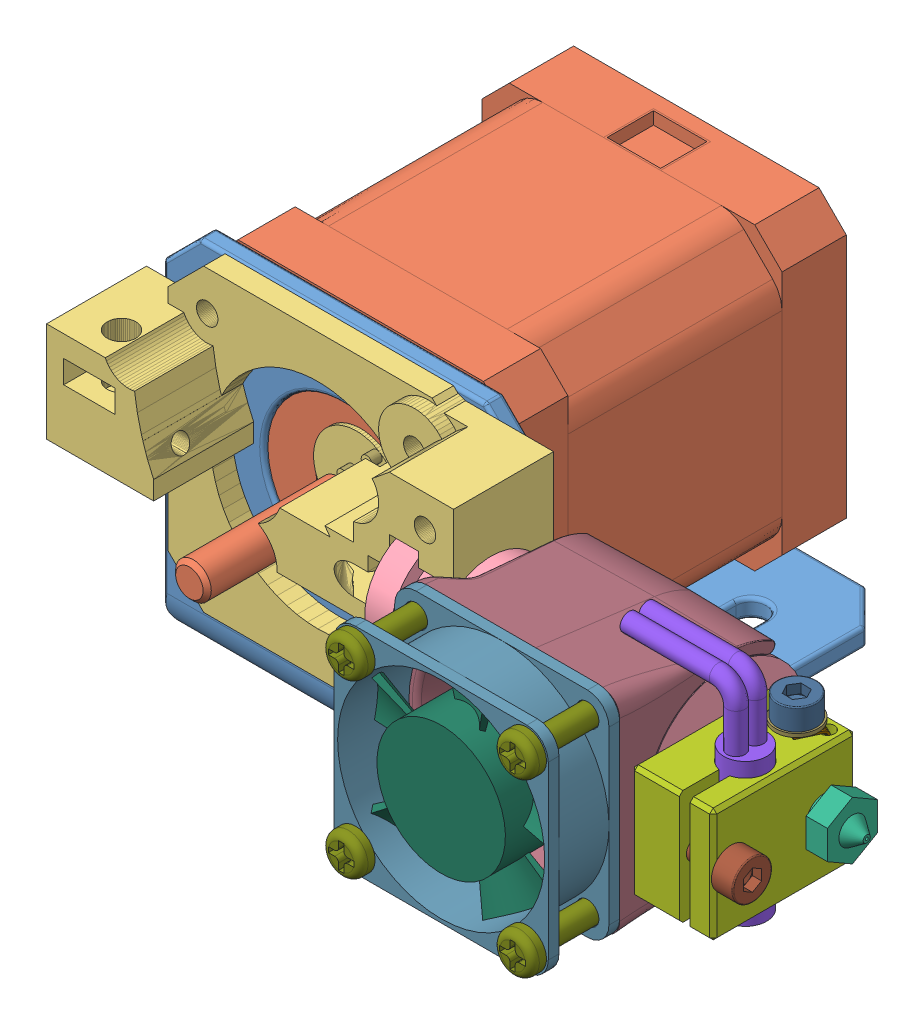
SolidWorks assembly Extruder, configuration Default. Lengths in mm.
Overall size (110.43 53.9 89.7).
21 component instances, 16 part files, 9 mates.
Components (placement in the parent):
- stepper motor mount-1: stepper motor mount [Default] at (17.4671 41.9715 62.2771) size (50.16 51.25 53.25)
- NEMA17_48-1: NEMA17_48 [Default] at (17.4671 41.9715 59.6771) size (42 42 71)
- extruder-2: extruder [Default] at (17.0666 41.9725 62.2771) x (0 1 0) z (0 0 1) size (42 57.13 22.4)
- E3D All Metal Hotend V6-1: E3D All Metal Hotend V6 [Default] at (80.7686 46.3695 71.7134) x (0 0 -1) z (1 0 0) size (38.16 34.25 62.3)
  - E3D v6 HotEnd - Heatsink-1: E3D v6 HotEnd - Heatsink [Default] at origin size (22.3 22.3 42.7)
  - E3D v6 HotEnd - Heatbreak-1: E3D v6 HotEnd - Heatbreak [Default] at (0 0 7.1) size (7 7 21.9)
  - E3D v6 HotEnd - Nozzle-1: E3D v6 HotEnd - Nozzle [Default] at (0 0 17.6) x (0.866025 0.5 0) z (0 0 1) size (8.08 7 12.5)
  - E3D v6 HotEnd - Heat Block-1: E3D v6 HotEnd - Heat Block [Default] at (-15.5 8 13.6) x (1 0 0) z (0 1 0) size (20 11.5 16)
  - Ceramic Cartridge Heater-1: Ceramic Cartridge Heater [Default] at (-7 10 9.6) x (1 0 0) z (0 1 0) size (6 18 29.25)
  - Thermistor-1: Thermistor [Default] at (2.5 3.65 11.6) x (0.903857 0 0.427835) z (0 -1 0) size (4.52 1.5 4.65)
  - HEXAGON SOCKET HEAD CAP SCREWS_SCB3-4-1: HEXAGON SOCKET HEAD CAP SCREWS_SCB3-4 [Default] at (1 9 8.8) x (0.999538 0 0.030402) z (0 1 0) size (5.5 5.5 7)
  - HEXAGON SOCKET HEAD CAP SCREWS_SCB3-10-1: HEXAGON SOCKET HEAD CAP SCREWS_SCB3-10 [Default] at (-13 0 13.6) size (5.5 5.5 13)
  - Flat Washers_PWF3-1: Flat Washers_PWF3 [Default] at (1 9 8.8) x (1 0 0) z (0 1 0) size (6 6 0.5)
  - E3D-v6 Fan Duct-1: E3D-v6 Fan Duct [Default] x (1 0 0) z (0 1 0) size (22.31 30.04 30)
  - Fan-DC-KDE0503PFB3-Promoco_Fan-DC-KDE0503PFB3-Promoco-1: Fan-DC-KDE0503PFB3-Promoco_Fan-DC-KDE0503PFB3-Promoco [Default] at (-15 0 -15) x (0 0 -1) z (-1 0 0) size (30 30 10)
    - Fan-House-30x30x10-Promoco_Fan-House-KDE0503PFB3-Promoco-1: Fan-House-30x30x10-Promoco_Fan-House-KDE0503PFB3-Promoco [Default] at origin size (30 30 10)
    - Fan-30x30x10-Promoco_Fan-KDE0503PFB3-Promoco-1: Fan-30x30x10-Promoco_Fan-KDE0503PFB3-Promoco [Default] x (0 0 -1) z (-0.999131 0.04169 0) size (8.5 27.91 28)
  - Self Tapping Screws - Pan Head_CSPTRSA-SUS-TP3-16-1: Self Tapping Screws - Pan Head_CSPTRSA-SUS-TP3-16 [Default] at (-25 -12 -27) size (18.01 5.5 5.5)
  - Self Tapping Screws - Pan Head_CSPTRSA-SUS-TP3-16-2: Self Tapping Screws - Pan Head_CSPTRSA-SUS-TP3-16 [Default] at (-25 12 -27) size (18.01 5.5 5.5)
  - Self Tapping Screws - Pan Head_CSPTRSA-SUS-TP3-16-3: Self Tapping Screws - Pan Head_CSPTRSA-SUS-TP3-16 [Default] at (-25 12 -3) size (18.01 5.5 5.5)
  - Self Tapping Screws - Pan Head_CSPTRSA-SUS-TP3-16-4: Self Tapping Screws - Pan Head_CSPTRSA-SUS-TP3-16 [Default] at (-25 -12 -3) size (18.01 5.5 5.5)
Mates (geometry in assembly coordinates):
- Coincident1: coincident anti-aligned: plane of stepper motor mount-1 through (17.4671 41.9715 59.6771) normal (0 0 -1); plane of NEMA17_48-1 through (17.4671 41.9715 59.6771) normal (0 0 1)
- Concentric1: concentric aligned: cylinder of stepper motor mount-1 through (1.9671 57.4715 62.2771) axis (0 0 1) radius 1.75; cylinder of NEMA17_48-1 through (1.9671 57.4715 55.1771) axis (0 0 1) radius 1.5
- Concentric2: concentric aligned: cylinder of stepper motor mount-1 through (32.9671 26.4715 62.2771) axis (0 0 1) radius 1.75; cylinder of NEMA17_48-1 through (32.9671 26.4715 55.1771) axis (0 0 1) radius 1.5
- Coincident7: coincident aligned: plane of stepper motor mount-1 through (17.4671 41.9715 62.2771) normal (0 0 1); plane of extruder-2 through (17.0706 20.9725 62.2771) normal (0 0 1)
- Width2: width aligned: plane of NEMA17_48-1 through (34.6509 62.9715 51.6771) normal (0 1 0); plane of NEMA17_48-1 through (34.6509 20.9715 51.6771) normal (0 -1 0); plane of extruder-2 through (17.0706 20.9725 65.2771) normal (0 1 0); plane of extruder-2 through (33.0686 62.9705 65.2771) normal (0 -1 0)
- Distance1: distance = 3.6055 mm anti-aligned: plane of extruder-2 through (-3.9274 41.9725 62.2771) normal (1 0 0); plane of stepper motor mount-1 through (-7.5329 41.9715 62.2771) normal (-1 0 0)
- Coincident11: coincident aligned: plane of extruder-2 through (38.0686 50.3745 74.6511) normal (-1 0 0); plane of E3D All Metal Hotend V6-1/E3D v6 HotEnd - Heatsink-1 through (38.0686 46.3695 71.7134) normal (-1 0 0)
- Width4: width aligned: plane of E3D All Metal Hotend V6-1/E3D v6 HotEnd - Heat Block-1 through (82.8686 38.3695 87.2134) normal (0 -1 0); plane of E3D All Metal Hotend V6-1/E3D v6 HotEnd - Heat Block-1 through (82.8686 54.3695 87.2134) normal (0 1 0); plane of extruder-2 through (38.0686 38.3185 71.7731) normal (0 -1 0); plane of extruder-2 through (42.1686 54.4205 71.7731) normal (0 1 0)
- Tangent2: tangent aligned: plane of extruder-2 through (42.1686 50.6445 67.4971) normal (0 0.738268 -0.674508); cylinder of E3D All Metal Hotend V6-1/E3D v6 HotEnd - Heatsink-1 through (80.7686 46.3695 71.7134) axis (1 0 0) radius 6
